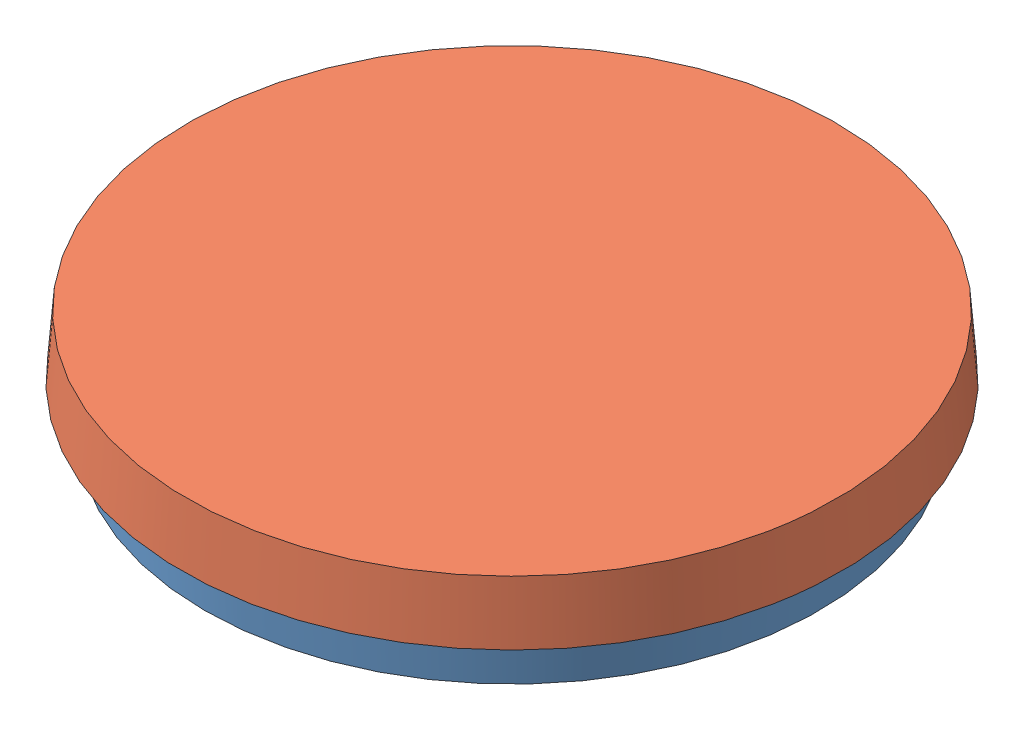
SolidWorks assembly Pitri Dish, configuration Default. Lengths in mm.
Overall size (105.98 15.9 105.98).
2 component instances, 2 part files, 2 mates.
Components (placement in the parent):
- Pitri Dish Bottom-1: Pitri Dish Bottom [Default] at (47.1593 37.2646 68.1376) size (89.71 14.88 89.71)
- Pitri Dish Top-1: Pitri Dish Top [Default] at (47.1593 52.403 68.1376) x (0.134295 0 -0.990941) z (-0.990941 0 -0.134295) size (94.18 8.66 94.18)
Mates (geometry in assembly coordinates):
- Concentric1: concentric anti-aligned: circle of Pitri Dish Bottom-1; circle of Pitri Dish Top-1
- Coincident2: coincident anti-aligned: plane of Pitri Dish Bottom-1 through (47.1593 51.387 68.1376) normal (0 1 0); plane of Pitri Dish Top-1 through (47.1593 51.387 68.1376) normal (0 -1 0)
